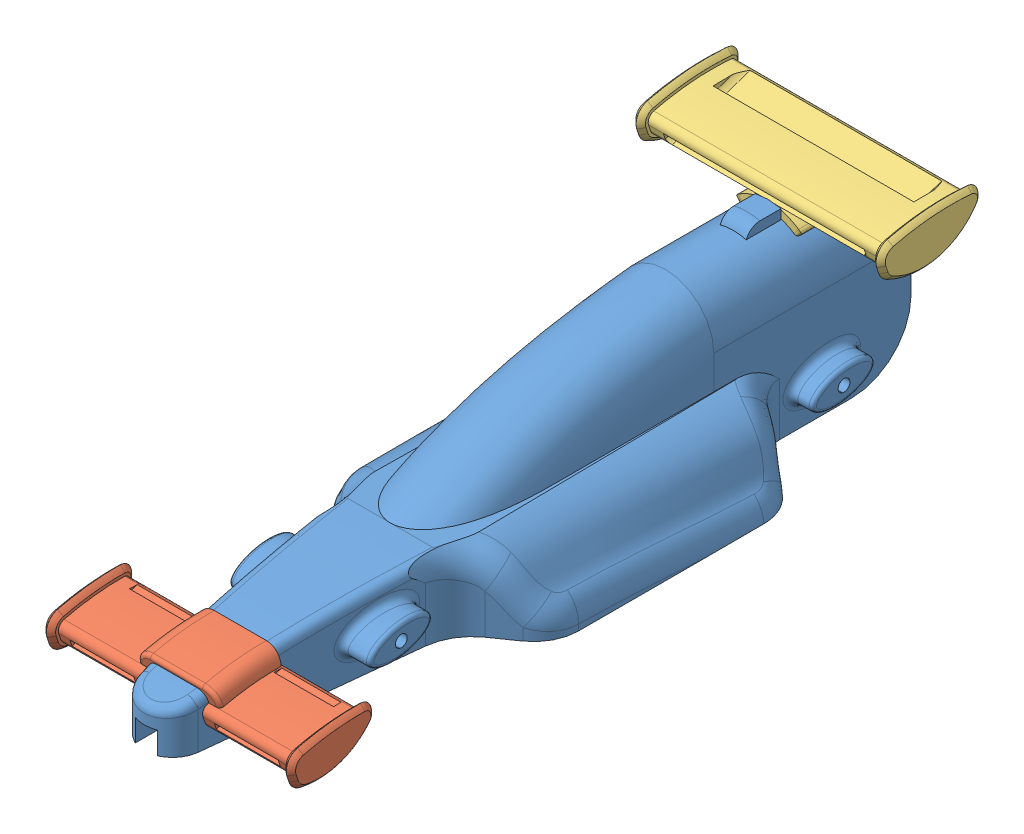
SolidWorks assembly wishwin_v2, configuration Predeterminado. Lengths in mm.
Overall size (67.01 54.23 193.11).
3 component instances, 3 part files, 6 mates.
Components (placement in the parent):
- cuerpo v2-1: cuerpo v2 [Predeterminado] at (0.9199 -20.6738 319.5556) size (62.49 45.27 193.11)
- aleron delantero-1: aleron delantero [Predeterminado] at (0.9199 -20.6738 319.5556) size (67.01 13.97 22.86)
- aleron trasero-1: aleron trasero [Predeterminado] at (0.9199 -19.4607 319.5506) size (67.01 14.21 27.33)
Mates (geometry in assembly coordinates):
- Coincidente1: coincident anti-aligned: plane of cuerpo v2-1 through (8.5561 -8.169 282.7911) normal (0.994522 0 0.104528); plane of aleron delantero-1 through (8.5561 -8.169 282.7911) normal (-0.994522 0 -0.104528)
- Coincidente2: coincident anti-aligned: plane of cuerpo v2-1 through (11.9199 -10.3181 280.2198) normal (0 0.240884 -0.970554); plane of aleron delantero-1 through (11.9199 -10.3181 280.2198) normal (0 -0.240884 0.970554)
- Tangente1: tangent: cylinder of cuerpo v2-1 through (11.9199 -72.4335 264.8033) axis (-1 0 0) radius 64; face of aleron delantero-1
- Ancho1: width: plane of aleron trasero-1 through (34.4199 55.8578 113.7806) normal (1 0 0); plane of aleron trasero-1 through (-32.5801 55.8578 113.7806) normal (-1 0 0); plane of cuerpo v2-1 through (13.9199 8.3262 -411.6219) normal (1 0 0); plane of cuerpo v2-1 through (-12.0801 8.3262 -411.6219) normal (-1 0 0)
- Coincidente9: coincident: plane of cuerpo v2-1 through (0.9199 8.3262 121.9556) normal (0 0 -1); plane of aleron trasero-1 through (0.9199 9.5393 121.9556) normal (0 0 1)
- Tangente4: tangent: cylinder of cuerpo v2-1 through (0.9199 8.3262 -411.6219) axis (0 0 1) radius 13; face of aleron trasero-1
